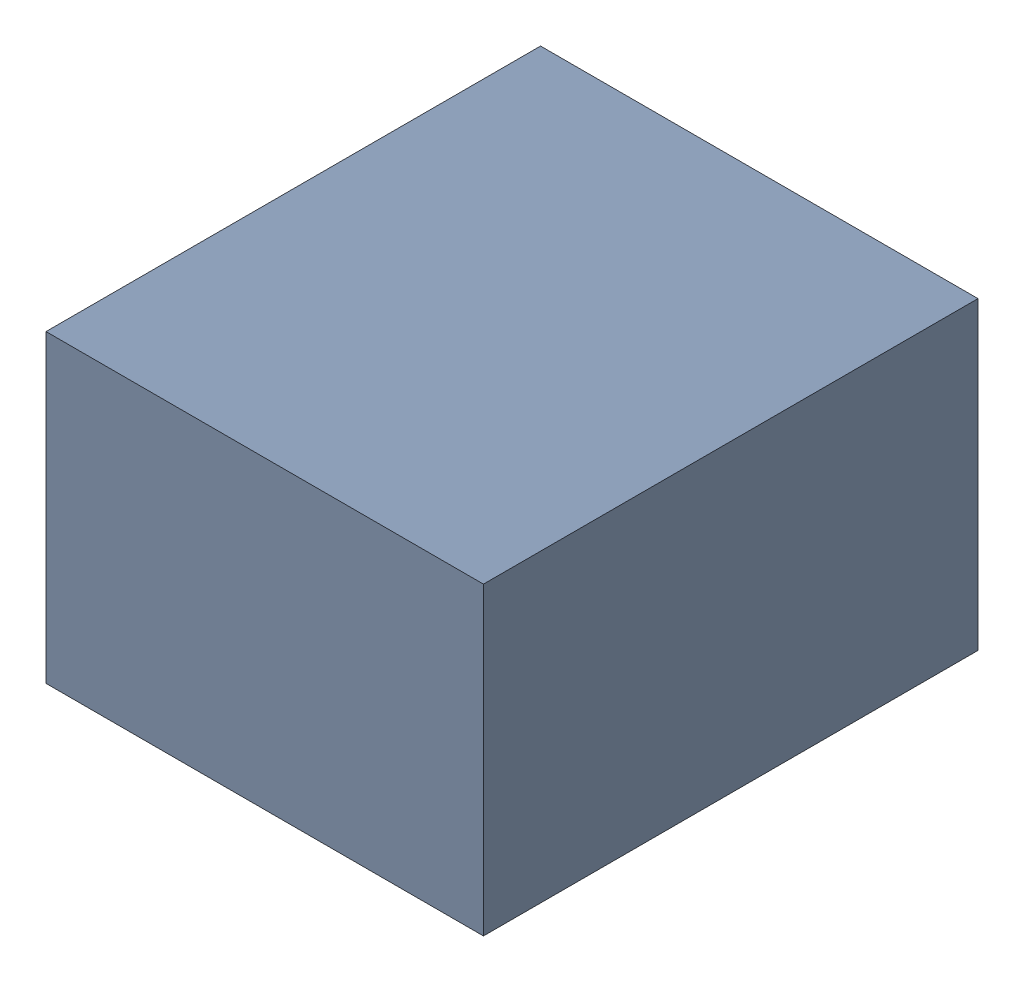
SolidWorks assembly RJ1, configuration Default. Lengths in mm.
Overall size (27.42 19.1 31).
2 component instances, 1 part files, 0 mates.
Components (placement in the parent):
- 402661776-1: 402661776 [Default] at (170.403 97.58 0) size (27.42 19.1 31)
  - Extruded_25-1: Extruded_25 [Default] at origin size (27.42 19.1 31)
